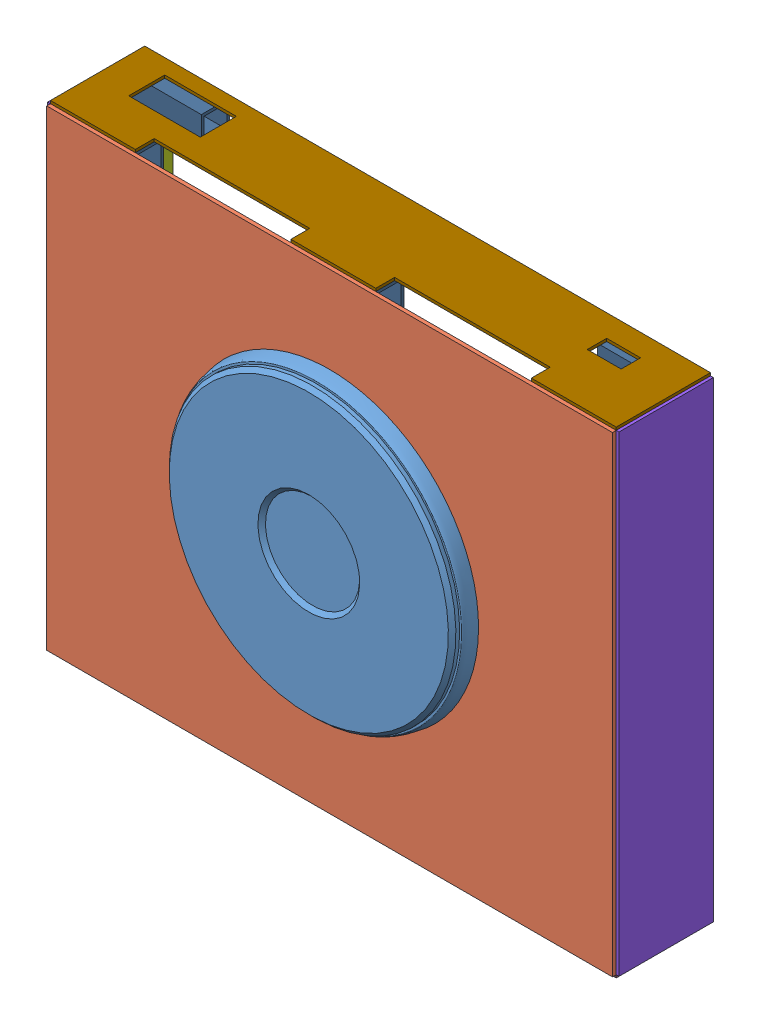
SolidWorks assembly AssemOven, configuration Default. Lengths in mm.
Overall size (303 253 63).
33 component instances, 14 part files, 41 mates.
Components (placement in the parent):
- Heater_170mm-1: Heater_170mm [Default] x (0.73 0.683447 0) z (0 0 1) size (158 158 55)
- Desk-1: Desk [Default] at (0 0 -9) size (300 250 2)
- tube 15x15x1.5 piece1-1: tube 15x15x1.5 piece1 [Default] at (100 0 -31.5) x (-1 0 0) z (0 1 0) size (200 15 15)
- tube 15x15x1.5 piece2-1: tube 15x15x1.5 piece2 [Default] at (-100 0 -16.5) x (1 0 0) z (0 1 0) size (25 15 15)
- tube 15x15x1.5 piece2-3: tube 15x15x1.5 piece2 [Default] at (100 0 -16.5) x (-1 0 0) z (0 -1 0) size (25 15 15)
- hex nut style 1 gradeab_iso-1: hex nut style 1 gradeab_iso [ISO - 4032 - M6 - W - N] at (0 0 -39) size (10 11.55 5.2)
- hex nut style 1 gradeab_iso-2: hex nut style 1 gradeab_iso [ISO - 4032 - M4 - W - N] at (-87.5 0 -42.2) x (-0.542442 -0.840093 0) z (0 0 -1) size (7 8.08 3.2)
- countersunk flat head cross recess screw_iso-4: countersunk flat head cross recess screw_iso [ISO 7046-1 - M4 x 40 - Z - 40C] at (-87.5 0 -7) x (0 0 -1) z (0.923728 0.383049 0) size (40 8.4 8.4)
- countersunk flat head cross recess screw_iso-5: countersunk flat head cross recess screw_iso [ISO 7046-1 - M4 x 40 - Z - 40C] at (87.5 0 -7) x (0 0 -1) z (0.923728 -0.383049 0) size (40 8.4 8.4)
- hex nut style 1 gradeab_iso-3: hex nut style 1 gradeab_iso [ISO - 4032 - M4 - W - N] at (87.5 0 -42.2) x (-0.542442 0.840093 0) z (0 0 -1) size (7 8.08 3.2)
- tube 15x15x1.5 piece4-1: tube 15x15x1.5 piece4 [Default] at (-142.5 0 -16.5) x (0 -1 0) z (-1 0 0) size (220 15 15)
- tube 15x15x1.5 piece4-2: tube 15x15x1.5 piece4 [Default] at (142.5 0 -16.5) x (0 -1 0) z (-1 0 0) size (220 15 15)
- Stripe 50x1.5 x250-1: Stripe 50x1.5 x250 [Default] at (150.75 0 -34) size (1.5 250 50)
- Stripe 50x1.5 x250-2: Stripe 50x1.5 x250 [Default] at (-150.75 0 -34) x (-1 0 0) z (0 0 -1) size (1.5 250 50)
- Stripe 50x1.5 x300-3: Stripe 50x1.5 x300 [Default] at (0 125.75 -34) x (0 -1 0) z (0 0 1) size (1.5 300 50)
- tube 15x15x1.5 backtop-1: tube 15x15x1.5 backtop [Default] at (150 117.5 -16.5) x (-1 0 0) z (0 0 1) size (45 15 15)
- Stripe 50x1.5 Front-1: Stripe 50x1.5 Front [Default] at (-57 -125.75 -34) x (0 1 0) z (0 0 1) size (1.5 186 50)
- Stripe 50x1.5 Inner-1: Stripe 50x1.5 Inner [Default] at (0 -109.25 -34) x (0 -1 0) z (0 0 1) size (1.5 270 50)
- tube 15x15x1.5 backtop-4: tube 15x15x1.5 backtop [Default] at (150 -117.5 -16.5) x (-1 0 0) z (0 0 1) size (45 15 15)
- tube 15x15x1.5 backtop-5: tube 15x15x1.5 backtop [Default] at (22.5 117.5 -16.5) x (-1 0 0) z (0 0 1) size (45 15 15)
- tube 15x15x1.5 backtop-6: tube 15x15x1.5 backtop [Default] at (22.5 -117.5 -16.5) x (-1 0 0) z (0 0 1) size (45 15 15)
- tube 15x15x1.5 backtop-7: tube 15x15x1.5 backtop [Default] at (-105 117.5 -16.5) x (-1 0 0) z (0 0 1) size (45 15 15)
- tube 15x15x1.5 backtop-8: tube 15x15x1.5 backtop [Default] at (-105 -117.5 -16.5) x (-1 0 0) z (0 0 1) size (45 15 15)
- Stripe 50x1.5 Front2-1: Stripe 50x1.5 Front2 [Default] at (123 -125.75 -34) x (0 1 0) z (0 0 1) size (1.5 54 50)
- tube 15x15x1.5 backtop-9: tube 15x15x1.5 backtop [Default] at (150 -117.5 -51.5) x (-1 0 0) z (0 0 1) size (45 15 15)
- tube 15x15x1.5 piece4-3: tube 15x15x1.5 piece4 [Default] at (142.5 0 -51.5) x (0 -1 0) z (-1 0 0) size (220 15 15)
- tube 15x15x1.5 piece4-4: tube 15x15x1.5 piece4 [Default] at (-142.5 0 -51.5) x (0 -1 0) z (-1 0 0) size (220 15 15)
- tube 15x15x1.5 backtop-10: tube 15x15x1.5 backtop [Default] at (150 117.5 -51.5) x (-1 0 0) z (0 0 1) size (45 15 15)
- tube 15x15x1.5 backtop-11: tube 15x15x1.5 backtop [Default] at (22.5 117.5 -51.5) x (-1 0 0) z (0 0 1) size (45 15 15)
- tube 15x15x1.5 backtop-12: tube 15x15x1.5 backtop [Default] at (-105 117.5 -51.5) x (-1 0 0) z (0 0 1) size (45 15 15)
- tube 15x15x1.5 backtop-13: tube 15x15x1.5 backtop [Default] at (-105 -117.5 -51.5) x (-1 0 0) z (0 0 1) size (45 15 15)
- tube 15x15x1.5 backtop-14: tube 15x15x1.5 backtop [Default] at (22.5 -117.5 -51.5) x (-1 0 0) z (0 0 1) size (45 15 15)
- Bottom-1: Bottom [Default] at (0 0 -61) size (300 250 2) (hidden)
Mates (geometry in assembly coordinates):
- Coincident2: coincident aligned: plane of Heater_170mm-1 through (0 0 0) normal (0 0 1); plane of assembly through (0 0 0) normal (0 0 1)
- Coincident4: coincident anti-aligned: plane of Heater_170mm-1 through (-52.56 -49.2082 -7) normal (0 0 -1); plane of Desk-1 through (0 0 -7) normal (0 0 1)
- Coincident5: coincident aligned: plane of Desk-1 through (0 0 -9) normal (0 1 0); plane of assembly through (0 0 0) normal (0 1 0)
- Coincident6: coincident aligned: plane of Desk-1 through (0 0 -9) normal (1 0 0); plane of assembly through (0 0 0) normal (1 0 0)
- Concentric3: concentric aligned: circle of Heater_170mm-1; circle of Desk-1
- Parallel2: parallel anti-aligned: plane of Desk-1 through (0 0 -9) normal (0 0 -1); plane of tube 15x15x1.5 piece1-1 through (-100 7.5 -24) normal (0 0 1)
- Concentric4: concentric anti-aligned: circle of Heater_170mm-1; circle of tube 15x15x1.5 piece1-1
- Concentric5: concentric aligned: circle of Heater_170mm-1; circle of tube 15x15x1.5 piece1-1
- Coincident13: coincident aligned: plane of tube 15x15x1.5 piece1-1 through (100 0 -31.5) normal (0 1 0); plane of assembly through (0 0 0) normal (0 1 0)
- Coincident15: coincident aligned: plane of tube 15x15x1.5 piece1-1 through (-100 0 -31.5) normal (-1 0 0); plane of tube 15x15x1.5 piece2-1 through (-100 0 -16.5) normal (-1 0 0)
- Coincident23: coincident anti-aligned: plane of Desk-1 through (0 0 -9) normal (0 0 -1); plane of tube 15x15x1.5 piece2-1 through (-75 7.5 -9) normal (0 0 1)
- Coincident24: coincident anti-aligned: plane of tube 15x15x1.5 piece1-1 through (-100 7.5 -24) normal (0 0 1); plane of tube 15x15x1.5 piece2-1 through (-75 7.5 -24) normal (0 0 -1)
- Concentric7: concentric aligned: circle of Heater_170mm-1; circle of hex nut style 1 gradeab_iso-1
- Coincident25: coincident anti-aligned: plane of tube 15x15x1.5 piece1-1 through (-100 7.5 -39) normal (0 0 -1); plane of hex nut style 1 gradeab_iso-1 through (-10 0 -39) normal (0 0 1)
- Coincident27: coincident anti-aligned: plane of tube 15x15x1.5 piece1-1 through (-100 7.5 -39) normal (0 0 -1); plane of hex nut style 1 gradeab_iso-2 through (-90.8952 2.1923 -39) normal (0 0 1)
- Coincident28: coincident aligned: plane of Desk-1 through (0 0 -7) normal (0 0 1); plane of countersunk flat head cross recess screw_iso-4 through (-87.5 0 -7) normal (0 0 1)
- Concentric9: concentric anti-aligned: cylinder of tube 15x15x1.5 piece2-1 through (-87.5 0 -9) axis (0 0 -1) radius 2; cylinder of countersunk flat head cross recess screw_iso-4 through (-87.5 0 -0.65) axis (0 0 1) radius 2
- Concentric10: concentric anti-aligned: cylinder of hex nut style 1 gradeab_iso-2 through (-87.5 0 -39) axis (0 0 -1) radius 1.65; cylinder of countersunk flat head cross recess screw_iso-4 through (-87.5 0 -0.65) axis (0 0 1) radius 2
- Coincident32: coincident anti-aligned: plane of Desk-1 through (0 0 -9) normal (0 0 -1); plane of tube 15x15x1.5 piece4-1 through (-150 -110 -9) normal (0 0 1)
- Coincident33: coincident anti-aligned: plane of tube 15x15x1.5 piece4-1; plane of assembly through (0 0 0) normal (0 1 0)
- Coincident34: coincident aligned: plane of Desk-1 through (-150 125 -7) normal (-1 0 0); plane of tube 15x15x1.5 piece4-1 through (-150 -110 -9) normal (-1 0 0)
- Coincident39: coincident anti-aligned: plane of tube 15x15x1.5 piece4-2 through (150 -110 -9) normal (1 0 0); plane of Stripe 50x1.5 x250-1 through (150 125 -59) normal (-1 0 0)
- Coincident40: coincident: line of tube 15x15x1.5 piece4-2 through (150 -110 -9) axis (0 1 0); plane of Stripe 50x1.5 x250-1 through (150 125 -9) normal (0 0 1)
- Coincident43: coincident: line of Desk-1 through (150 125 -9) axis (-1 0 0); plane of Stripe 50x1.5 x300-3 through (150 126.5 -9) normal (0 0 1)
- Coincident45: coincident anti-aligned: plane of Desk-1 through (0 0 -9) normal (0 0 -1); plane of tube 15x15x1.5 backtop-1 through (105 110 -9) normal (0 0 1)
- Coincident47: coincident: line of Desk-1 through (150 125 -7) axis (0 0 -1); plane of Stripe 50x1.5 x300-3 through (150 125.75 -34) normal (1 0 0)
- Coincident48: coincident anti-aligned: plane of Desk-1 through (-150 125 -7) normal (0 1 0); plane of Stripe 50x1.5 x300-3 through (150 125 -59) normal (0 -1 0)
- Coincident49: coincident aligned: plane of Stripe 50x1.5 x300-3 through (150 125.75 -34) normal (1 0 0); plane of tube 15x15x1.5 backtop-1 through (150 117.5 -16.5) normal (1 0 0)
- Coincident50: coincident anti-aligned: plane of tube 15x15x1.5 piece4-2 through (142.5 110 -16.5) normal (0 1 0); plane of tube 15x15x1.5 backtop-1 through (105 110 -9) normal (0 -1 0)
- Coincident53: coincident: line of Desk-1 through (-150 -125 -9) axis (1 0 0); plane of Stripe 50x1.5 Front-1 through (-150 -126.5 -9) normal (0 0 1)
- Coincident55: coincident anti-aligned: plane of Desk-1 through (0 0 -9) normal (0 0 -1); plane of Stripe 50x1.5 Inner-1 through (135 -108.5 -9) normal (0 0 1)
- Coincident56: coincident anti-aligned: plane of tube 15x15x1.5 piece4-1 through (-135 -110 -9) normal (1 0 0); plane of Stripe 50x1.5 Inner-1 through (-135 -109.25 -34) normal (-1 0 0)
- Coincident57: coincident anti-aligned: plane of Desk-1 through (-150 -125 -7) normal (0 -1 0); plane of Stripe 50x1.5 Front-1 through (-150 -125 -59) normal (0 1 0)
- Coincident58: coincident anti-aligned: plane of Stripe 50x1.5 Inner-1 through (135 -110 -59) normal (0 -1 0); plane of tube 15x15x1.5 backtop-8 through (-150 -110 -9) normal (0 1 0)
- Coincident59: coincident aligned: plane of Desk-1 through (-150 125 -7) normal (-1 0 0); plane of Stripe 50x1.5 Front-1 through (-150 -125.75 -34) normal (-1 0 0)
- Coincident60: coincident anti-aligned: plane of tube 15x15x1.5 backtop-4 through (105 -125 -9) normal (0 -1 0); plane of Stripe 50x1.5 Front2-1 through (96 -125 -59) normal (0 1 0)
- Coincident61: coincident aligned: plane of Desk-1 through (150 125 -7) normal (1 0 0); plane of Stripe 50x1.5 Front2-1 through (150 -125.75 -34) normal (1 0 0)
- Coincident62: coincident anti-aligned: plane of Desk-1 through (0 0 -9) normal (0 0 -1); plane of Stripe 50x1.5 Front2-1 through (96 -126.5 -9) normal (0 0 1)
- Coincident63: coincident aligned: plane of Desk-1 through (-150 125 -7) normal (0 1 0); plane of Bottom-1 through (-150 125 -59) normal (0 1 0)
- Coincident64: coincident aligned: plane of Desk-1 through (150 125 -7) normal (1 0 0); plane of Bottom-1 through (150 125 -59) normal (1 0 0)
- Coincident65: coincident anti-aligned: plane of Stripe 50x1.5 x250-1 through (150 125 -59) normal (0 0 -1); plane of Bottom-1 through (0 0 -59) normal (0 0 1)
